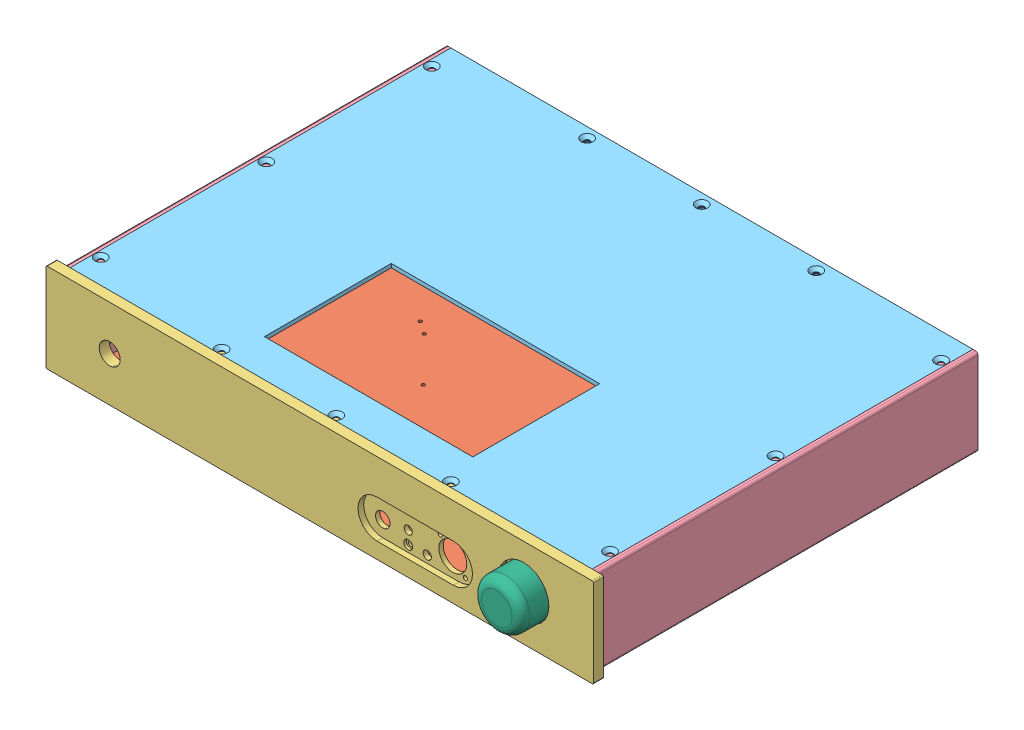
SolidWorks assembly 組合件, configuration 預設. Lengths in mm.
Overall size (430 70 329).
7 component instances, 6 part files, 17 mates.
Components (placement in the parent):
- Back-1: Back [預設] at (-57.5395 43.3439 403.5) size (410 62 13)
- Bottom-1: Bottom [預設] at (-57.5395 9.3439 553.5) size (410 3 300)
- Front-1: Front [預設] at (-57.5395 43.3439 711.5) x (-1 0 0) z (0 0 -1) size (430 70 18)
- Side-1: Side [預設] at (149.4605 43.3439 703.5) x (0 0 -1) z (1 0 0) size (300 68 14)
- TOP-1: TOP [預設] at (-57.5395 74.3439 553.5) size (410 3 300)
- Side-2: Side [預設] at (-264.5395 43.3439 703.5) x (0 0 -1) z (-1 0 0) size (300 68 14)
- knob-1: knob [預設] at (102.4605 43.3439 707.5) x (0.503019 -0.864275 0) z (0 0 1) size (38 38 25)
Mates (geometry in assembly coordinates):
- 重合/共線/共點10: coincident: plane of assembly; plane of assembly; plane of Side-1 through (147.4605 9.3439 403.5) normal (-1 0 0); plane of TOP-1 through (147.4605 77.3439 703.5) normal (1 0 0)
- 重合/共線/共點14: coincident: plane of assembly; plane of assembly; plane of Back-1 through (-57.5395 43.3439 403.5) normal (0 0 -1); plane of Bottom-1 through (-262.5395 12.3439 403.5) normal (0 0 -1)
- 重合/共線/共點15: coincident: plane of assembly; plane of assembly; plane of Back-1 through (-262.5395 12.3439 406.5) normal (0 -1 0); plane of Bottom-1 through (-57.5395 12.3439 553.5) normal (0 1 0)
- 重合/共線/共點16: coincident: plane of assembly; plane of assembly; plane of Back-1 through (-262.5395 74.3439 406.5) normal (0 1 0); plane of TOP-1 through (-57.5395 74.3439 553.5) normal (0 -1 0)
- 重合/共線/共點17: coincident: plane of assembly; plane of assembly; plane of Back-1 through (-57.5395 43.3439 403.5) normal (0 0 -1); plane of TOP-1 through (-262.5395 77.3439 403.5) normal (0 0 -1)
- 重合/共線/共點18: coincident: plane of assembly; plane of assembly; plane of Back-1 through (-262.5395 12.3439 406.5) normal (-1 0 0); plane of TOP-1 through (-262.5395 77.3439 703.5) normal (-1 0 0)
- 重合/共線/共點19: coincident: plane of assembly; plane of assembly; plane of Side-1 through (137.4605 74.3439 403.5) normal (0 1 0); plane of TOP-1 through (-57.5395 74.3439 553.5) normal (0 -1 0)
- 重合/共線/共點20: coincident: plane of assembly; plane of assembly; plane of Back-1 through (-57.5395 43.3439 406.5) normal (0 0 1); plane of Side-1 through (147.4605 12.3439 406.5) normal (0 0 -1)
- 重合/共線/共點21: coincident: plane of assembly; plane of assembly; plane of Back-1 through (-57.5395 43.3439 406.5) normal (0 0 1); plane of Side-2 through (-262.5395 74.3439 406.5) normal (0 0 -1)
- 重合/共線/共點22: coincident: plane of assembly; plane of assembly; plane of TOP-1 through (-57.5395 74.3439 553.5) normal (0 -1 0); plane of Side-2 through (-252.5395 74.3439 403.5) normal (0 1 0)
- 重合/共線/共點23: coincident: plane of assembly; plane of assembly; plane of Back-1 through (-262.5395 12.3439 406.5) normal (-1 0 0); plane of Side-2 through (-262.5395 77.3439 403.5) normal (1 0 0)
- 重合/共線/共點27: coincident: plane of assembly; plane of assembly; plane of Front-1 through (-57.5395 43.3439 703.5) normal (0 0 -1); plane of Side-2 through (-264.5395 43.3439 703.5) normal (0 0 1)
- 重合/共線/共點28: coincident: plane of assembly; plane of assembly; plane of Front-1 through (137.4605 74.3439 693.5) normal (0 1 0); plane of TOP-1 through (-57.5395 74.3439 553.5) normal (0 -1 0)
- 重合/共線/共點29: coincident: plane of assembly; plane of assembly; plane of Front-1 through (-252.5395 74.3439 693.5) normal (-1 0 0); plane of Side-2 through (-252.5395 43.3439 703.5) normal (1 0 0)
- 重合/共線/共點30: coincident: plane of assembly; plane of assembly; plane of Bottom-1 through (-262.5395 12.3439 703.5) normal (-1 0 0); plane of Side-2 through (-262.5395 77.3439 403.5) normal (1 0 0)
- 同軸心1: concentric: circle of assembly; circle of assembly; circle of Front-1; circle of knob-1
- 重合/共線/共點32: coincident: plane of assembly; plane of assembly; plane of Front-1 through (102.4605 43.9533 707.5) normal (0 0 1); plane of knob-1 through (102.4605 43.3439 707.5) normal (0 0 -1)
